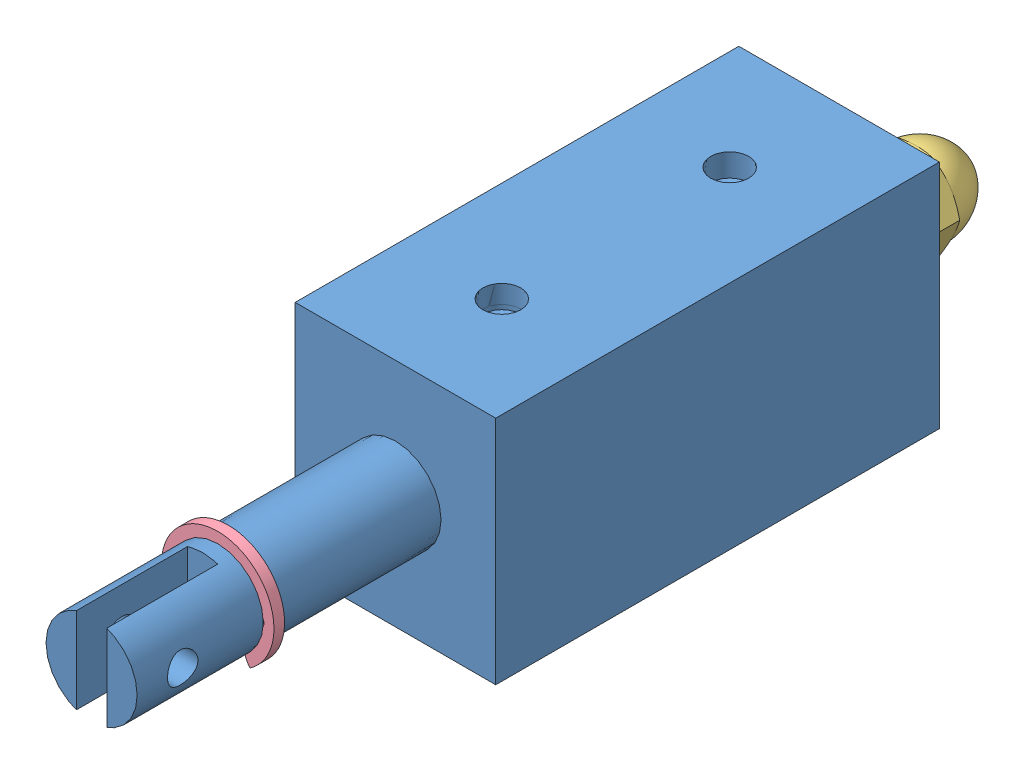
SolidWorks assembly Solenoid, configuration Default. Lengths in mm.
Overall size (13.2 15.2 57.52).
4 component instances, 4 part files, 6 mates.
Components (placement in the parent):
- Base-1: Base [Default] at origin size (13.2 15.2 57)
- 9262K161_MULTIPURPOSE O-RING-1: 9262K161_MULTIPURPOSE O-RING [9262K161] at (0 0 -30.7) size (7 7 2)
- 94000A330_18-8 SS CAP NUT-1: 94000A330_18-8 SS CAP NUT [94000A330] at (0 0 -31.5447) x (0.893318 -0.449425 0) z (0 0 1) size (5.5 6.35 5.98)
- 90119A108_LOW-CLEARANCE EXTERNAL RETAINING RING-1: 90119A108_LOW-CLEARANCE EXTERNAL RETAINING RING [90119A108] at (0 0 11) size (7.4 6.73 0.7)
Mates (geometry in assembly coordinates):
- Concentric1: concentric: cylinder of Base-1 through (0 0 -41.2426) axis (0 0 1) radius 1.5; line of 9262K161_MULTIPURPOSE O-RING-1 through (0 0 -29.7) axis (0 0 -1)
- Concentric2: concentric: cylinder of Base-1 through (0 0 -32) axis (0 0 -1) radius 1.2195; line of 94000A330_18-8 SS CAP NUT-1 through (0 0 -34.2113) axis (0 0 -1)
- Concentric3: concentric: cylinder of Base-1 through (0 0 20) axis (0 0 1) radius 2.5; cylinder of 90119A108_LOW-CLEARANCE EXTERNAL RETAINING RING-1 through (0 0 11.7) axis (0 0 -1) radius 2.4
- Coincident5: coincident: plane of Base-1 through (3 0 11.7) normal (0 0 -1); plane of 90119A108_LOW-CLEARANCE EXTERNAL RETAINING RING-1 through (-2.2956 0.0565 11.7) normal (0 0 1)
- Tangent4: tangent: torus of 9262K161_MULTIPURPOSE O-RING-1; plane of Base-1 through (0 0 -29.7) normal (0 0 -1)
- Coincident6: coincident: circle of Base-1; cone of 94000A330_18-8 SS CAP NUT-1 through (0 0 -37.5774) axis (0 0 -1)
